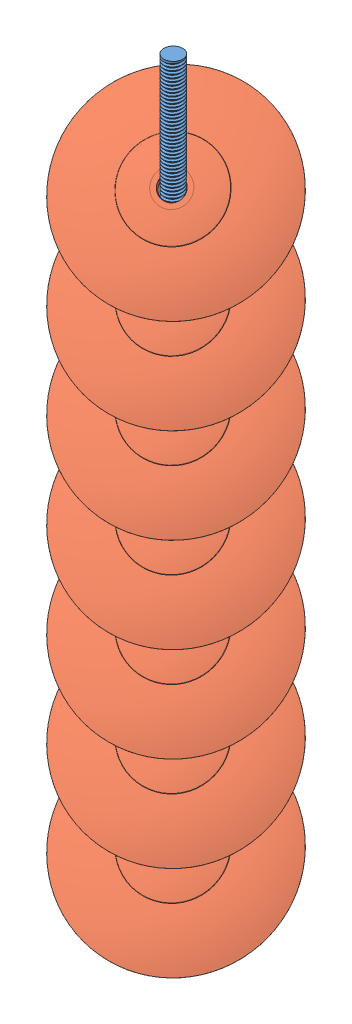
SolidWorks assembly new assemblly, configuration Default. Lengths in mm.
Overall size (132.53 510.07 112.09).
8 component instances, 2 part files, 2 mates.
Components (placement in the parent):
- threadrod-1: threadrod [Default] at (261.3942 43.2918 494.511) size (12.32 510.07 18.18)
- FRONTAL BLADE SET-1: FRONTAL BLADE SET [Default] at (233.8109 239.0393 452.7616) x (0.903007 -0.420239 -0.089313) z (-0.387568 -0.707107 -0.591432) size (117.05 117.05 13.26)
- FRONTAL BLADE SET-2: FRONTAL BLADE SET [Default] at (233.8109 179.0393 452.7616) x (0.903007 -0.420239 -0.089313) z (-0.387568 -0.707107 -0.591432) size (117.05 117.05 13.26)
- FRONTAL BLADE SET-3: FRONTAL BLADE SET [Default] at (233.8109 119.0393 452.7616) x (0.903007 -0.420239 -0.089313) z (-0.387568 -0.707107 -0.591432) size (117.05 117.05 13.26)
- FRONTAL BLADE SET-4: FRONTAL BLADE SET [Default] at (233.8109 59.0393 452.7616) x (0.903007 -0.420239 -0.089313) z (-0.387568 -0.707107 -0.591432) size (117.05 117.05 13.26)
- FRONTAL BLADE SET-6: FRONTAL BLADE SET [Default] at (233.8109 299.0393 452.7616) x (0.903007 -0.420239 -0.089313) z (-0.387568 -0.707107 -0.591432) size (117.05 117.05 13.26)
- FRONTAL BLADE SET-7: FRONTAL BLADE SET [Default] at (233.8109 359.0393 452.7616) x (0.903007 -0.420239 -0.089313) z (-0.387568 -0.707107 -0.591432) size (117.05 117.05 13.26)
- FRONTAL BLADE SET-8: FRONTAL BLADE SET [Default] at (233.8109 419.0393 452.7616) x (0.903007 -0.420239 -0.089313) z (-0.387568 -0.707107 -0.591432) size (117.05 117.05 13.26)
Mates (geometry in assembly coordinates):
- Angle5: planar angle = 0.785398 rad: plane of FRONTAL BLADE SET-1 through (262.5967 291.5582 496.6889) normal (0.387568 0.707107 0.591432); plane of threadrod-1 through (261.3942 543.2918 494.511) normal (0 1 0)
- Tangent11: tangent: curve of threadrod-1; circle of FRONTAL BLADE SET-1
